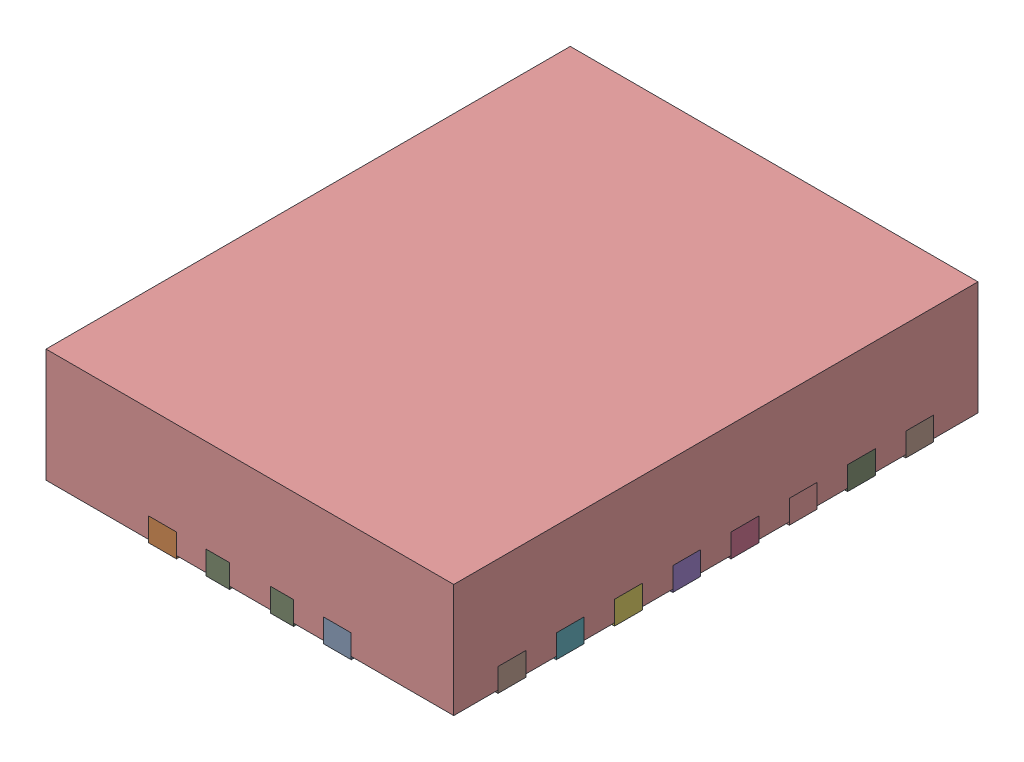
SolidWorks assembly RHL0020A, configuration Standard. Lengths in mm.
Overall size (3.5 1 4.5).
23 component instances, 22 part files, 0 mates.
Components (placement in the parent):
- FRAME-RHL0020A-1: FRAME-RHL0020A [Standard] at (0 -0.025 0) size (3.5 0.2 4.5)
  - FRAME-RHL0020A-Part-1-1: FRAME-RHL0020A-Part-1 [Standard] at origin size (0.24 0.2 0.4)
  - FRAME-RHL0020A-Part-2-1: FRAME-RHL0020A-Part-2 [Standard] at origin size (0.24 0.2 0.4)
  - FRAME-RHL0020A-Part-3-1: FRAME-RHL0020A-Part-3 [Standard] at origin size (0.24 0.2 0.4)
  - FRAME-RHL0020A-Part-4-1: FRAME-RHL0020A-Part-4 [Standard] at origin size (0.24 0.2 0.4)
  - FRAME-RHL0020A-Part-5-1: FRAME-RHL0020A-Part-5 [Standard] at origin size (0.4 0.2 0.24)
  - FRAME-RHL0020A-Part-6-1: FRAME-RHL0020A-Part-6 [Standard] at origin size (0.4 0.2 0.24)
  - FRAME-RHL0020A-Part-7-1: FRAME-RHL0020A-Part-7 [Standard] at origin size (0.4 0.2 0.24)
  - FRAME-RHL0020A-Part-8-1: FRAME-RHL0020A-Part-8 [Standard] at origin size (0.4 0.2 0.24)
  - FRAME-RHL0020A-Part-9-1: FRAME-RHL0020A-Part-9 [Standard] at origin size (0.4 0.2 0.24)
  - FRAME-RHL0020A-Part-10-1: FRAME-RHL0020A-Part-10 [Standard] at origin size (0.4 0.2 0.24)
  - FRAME-RHL0020A-Part-11-1: FRAME-RHL0020A-Part-11 [Standard] at origin size (0.4 0.2 0.24)
  - FRAME-RHL0020A-Part-12-1: FRAME-RHL0020A-Part-12 [Standard] at origin size (0.4 0.2 0.24)
  - FRAME-RHL0020A-Part-13-1: FRAME-RHL0020A-Part-13 [Standard] at origin size (0.4 0.2 0.24)
  - FRAME-RHL0020A-Part-14-1: FRAME-RHL0020A-Part-14 [Standard] at origin size (0.4 0.2 0.24)
  - FRAME-RHL0020A-Part-15-1: FRAME-RHL0020A-Part-15 [Standard] at origin size (0.4 0.2 0.24)
  - FRAME-RHL0020A-Part-16-1: FRAME-RHL0020A-Part-16 [Standard] at origin size (0.4 0.2 0.24)
  - FRAME-RHL0020A-Part-17-1: FRAME-RHL0020A-Part-17 [Standard] at origin size (0.4 0.2 0.24)
  - FRAME-RHL0020A-Part-18-1: FRAME-RHL0020A-Part-18 [Standard] at origin size (0.4 0.2 0.24)
  - FRAME-RHL0020A-Part-19-1: FRAME-RHL0020A-Part-19 [Standard] at origin size (0.4 0.2 0.24)
  - FRAME-RHL0020A-Part-20-1: FRAME-RHL0020A-Part-20 [Standard] at origin size (0.4 0.2 0.24)
  - FRAME-RHL0020A-Part-21-1: FRAME-RHL0020A-Part-21 [Standard] at origin size (2.25 0.2 4.5)
- BODY-QFN-1: BODY-QFN [Standard] at origin size (3.5 0.97 4.5)
